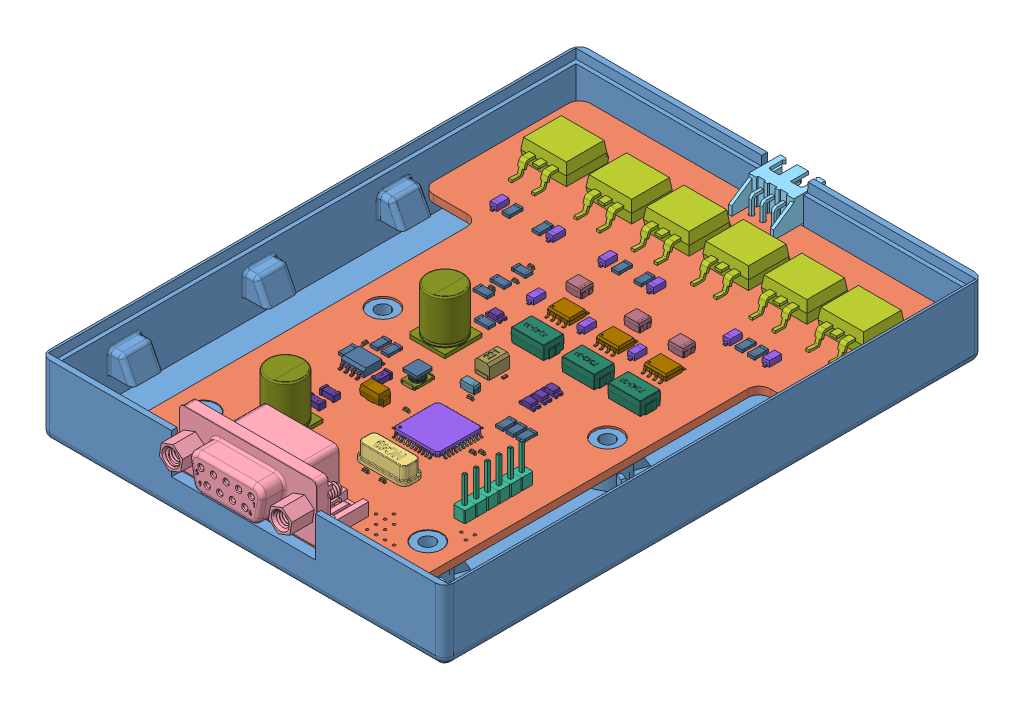
SolidWorks assembly Общая сборка, configuration По умолчанию. Lengths in mm.
Overall size (90 25.25 126.59).
248 component instances, 92 part files, 4 mates.
Components (placement in the parent):
- основание-1: основание [По умолчанию] at origin size (90 16 120)
- PCB_BLDC421232_СБ-1: PCB_BLDC421232_СБ [По умолчанию] at (1.5 8.4374 57.75) x (0 0 -1) z (0 1 0) size (126.59 85 25.25)
  - Board-1: Board [По умолчанию] at origin size (115 85 1.69)
  - ZQ1-1: ZQ1 [По умолчанию] at origin size (4.65 11.35 16.3)
    - User_Library-HC49_Crystal-1: User_Library-HC49_Crystal [По умолчанию] at (22.338 -6.587 0) x (0 1 0) z (1 0 0) size (11.35 16.3 4.65)
  - XS1-1: XS1 [По умолчанию] at origin size (16.7 30.5 16.4)
    - User_Library-DB-9F-1: User_Library-DB-9F [По умолчанию] at (-1.1101 1.395 6.3) x (0 -1 0) z (-1 0 0) size (30.5 16.4 16.7)
  - XP2-1: XP2 [По умолчанию] at origin size (11.5 10 9.25)
    - User_Library-DS1069-3_CWF-3R-1: User_Library-DS1069-3_CWF-3R [По умолчанию] at (111.5999 -2.9999 0) x (0 1 0) z (0 0 1) size (10 11.5 9.25)
  - XP1-1: XP1 [По умолчанию] at origin size (15.24 2.54 11.54)
    - User_Library-PLS-2-1: User_Library-PLS-2 [По умолчанию] at (19.9299 -25.8001 0) x (1 0 0) z (0 -1 0) size (5.08 11.54 2.54)
    - User_Library-PLS-2-2: User_Library-PLS-2 [По умолчанию] at (25.0099 -25.8001 0) x (1 0 0) z (0 -1 0) size (5.08 11.54 2.54)
    - User_Library-PLS-2-3: User_Library-PLS-2 [По умолчанию] at (30.0899 -25.8001 0) x (1 0 0) z (0 -1 0) size (5.08 11.54 2.54)
  - VT6-1: VT6 [По умолчанию] at origin size (15.26 10.16 5.02)
    - SW3dPS-DPAK-1: SW3dPS-DPAK [По умолчанию] at (100.6751 -33.2751 2.5) x (0 -1 0) z (-1 0 0) size (10.16 5.02 15.26)
  - VT5-1: VT5 [По умолчанию] at origin size (15.26 10.16 5.02)
    - SW3dPS-DPAK-1: SW3dPS-DPAK [По умолчанию] at (100.5951 -20.7351 2.5) x (0 -1 0) z (-1 0 0) size (10.16 5.02 15.26)
  - VT4-1: VT4 [По умолчанию] at origin size (15.26 10.16 5.02)
    - SW3dPS-DPAK-1: SW3dPS-DPAK [По умолчанию] at (100.5951 -7.7351 2.5) x (0 -1 0) z (-1 0 0) size (10.16 5.02 15.26)
  - VT3-1: VT3 [По умолчанию] at origin size (15.26 10.16 5.02)
    - SW3dPS-DPAK-1: SW3dPS-DPAK [По умолчанию] at (100.5951 5.5149 2.5) x (0 -1 0) z (-1 0 0) size (10.16 5.02 15.26)
  - VT2-1: VT2 [По умолчанию] at origin size (15.26 10.16 5.02)
    - SW3dPS-DPAK-1: SW3dPS-DPAK [По умолчанию] at (100.4251 18.1019 2.5) x (0 -1 0) z (-1 0 0) size (10.16 5.02 15.26)
  - VT1-1: VT1 [По умолчанию] at origin size (15.26 10.16 5.02)
    - SW3dPS-DPAK-1: SW3dPS-DPAK [По умолчанию] at (100.3451 32.5619 2.5) x (0 -1 0) z (-1 0 0) size (10.16 5.02 15.26)
  - VD10-1: VD10 [По умолчанию] at origin size (3.7 1.6 1.27)
    - SW3DPS-SOD123-DEFAULT-1: SW3DPS-SOD123-DEFAULT [По умолчанию] at (85.3569 -28.75 0) x (-1 0 0) z (0 1 0) size (3.7 1.27 1.6)
  - VD9-1: VD9 [По умолчанию] at origin size (3.7 1.6 1.27)
    - SW3DPS-SOD123-DEFAULT-1: SW3DPS-SOD123-DEFAULT [По умолчанию] at (85.1069 -20.25 0) x (-1 0 0) z (0 1 0) size (3.7 1.27 1.6)
  - VD8-1: VD8 [По умолчанию] at origin size (3.7 1.6 1.27)
    - SW3DPS-SOD123-DEFAULT-1: SW3DPS-SOD123-DEFAULT [По умолчанию] at (86.6069 -1.75 0) x (-1 0 0) z (0 1 0) size (3.7 1.27 1.6)
  - VD7-1: VD7 [По умолчанию] at origin size (3.7 1.6 1.27)
    - SW3DPS-SOD123-DEFAULT-1: SW3DPS-SOD123-DEFAULT [По умолчанию] at (86.3569 8.75 0) x (-1 0 0) z (0 1 0) size (3.7 1.27 1.6)
  - VD6-1: VD6 [По умолчанию] at origin size (3.7 1.6 1.27)
    - SW3DPS-SOD123-DEFAULT-1: SW3DPS-SOD123-DEFAULT [По умолчанию] at (85.3649 19.377 0) x (-1 0 0) z (0 1 0) size (3.7 1.27 1.6)
  - VD5-1: VD5 [По умолчанию] at origin size (3.7 1.6 1.27)
    - SW3DPS-SOD123-DEFAULT-1: SW3DPS-SOD123-DEFAULT [По умолчанию] at (85.1069 31.6269 0) x (-1 0 0) z (0 1 0) size (3.7 1.27 1.6)
  - VD4-1: VD4 [По умолчанию] at origin size (3.7 1.6 1.27)
    - SW3DPS-SOD123-DEFAULT-1: SW3DPS-SOD123-DEFAULT [По умолчанию] at (71.6431 -12.5 0) x (1 0 0) z (0 -1 0) size (3.7 1.27 1.6)
  - VD3-1: VD3 [По умолчанию] at origin size (3.7 1.6 1.27)
    - SW3DPS-SOD123-DEFAULT-1: SW3DPS-SOD123-DEFAULT [По умолчанию] at (71.1431 -1.75 0) x (1 0 0) z (0 -1 0) size (3.7 1.27 1.6)
  - VD2-1: VD2 [По умолчанию] at origin size (3.7 1.6 1.27)
    - SW3DPS-SOD123-DEFAULT-1: SW3DPS-SOD123-DEFAULT [По умолчанию] at (71.1431 9.5 0) x (1 0 0) z (0 -1 0) size (3.7 1.27 1.6)
  - VD1-1: VD1 [По умолчанию] at origin size (2.6 5.21 2.43)
    - SW3dPS-DO-214AC_SMA-1: SW3dPS-DO-214AC_SMA [По умолчанию] at (33.9999 8.2001 1.5) x (1 0 0) z (0 0 1) size (2.6 5.21 2.43)
  - R24-1: R24 [По умолчанию] at origin size (1.66 3.1 0.62)
    - ЁхчшёЄюЁ-1206-1: ЁхчшёЄюЁ-1206 [По умолчанию] at (60.7501 10.4999 0.09) x (0 -1 0) z (-1 0 0) size (3.1 0.62 1.66)
  - R23-1: R23 [По умолчанию] at origin size (3.1 1.66 0.62)
    - ЁхчшёЄюЁ-1206-1: ЁхчшёЄюЁ-1206 [По умолчанию] at (85.2501 -25.7499 0.09) x (1 0 0) z (0 -1 0) size (3.1 0.62 1.66)
  - R22-1: R22 [По умолчанию] at origin size (3.1 1.66 0.62)
    - ЁхчшёЄюЁ-1206-1: ЁхчшёЄюЁ-1206 [По умолчанию] at (85.2501 -22.9999 0.09) x (1 0 0) z (0 -1 0) size (3.1 0.62 1.66)
  - R21-1: R21 [По умолчанию] at origin size (3.1 1.66 0.62)
    - ЁхчшёЄюЁ-1206-1: ЁхчшёЄюЁ-1206 [По умолчанию] at (86.7501 1.0001 0.09) x (1 0 0) z (0 -1 0) size (3.1 0.62 1.66)
  - R20-1: R20 [По умолчанию] at origin size (3.1 1.66 0.62)
    - ЁхчшёЄюЁ-1206-1: ЁхчшёЄюЁ-1206 [По умолчанию] at (86.5001 5.7501 0.09) x (1 0 0) z (0 -1 0) size (3.1 0.62 1.66)
  - R19-1: R19 [По умолчанию] at origin size (3.1 1.66 0.62)
    - ЁхчшёЄюЁ-1206-1: ЁхчшёЄюЁ-1206 [По умолчанию] at (85.2501 22.1271 0.09) x (1 0 0) z (0 -1 0) size (3.1 0.62 1.66)
  - R18-1: R18 [По умолчанию] at origin size (3.1 1.66 0.62)
    - ЁхчшёЄюЁ-1206-1: ЁхчшёЄюЁ-1206 [По умолчанию] at (85.2501 28.8771 0.09) x (1 0 0) z (0 -1 0) size (3.1 0.62 1.66)
  - R17-1: R17 [По умолчанию] at origin size (1 0.5 0.25)
    - User_Library-d0402h025-1: User_Library-d0402h025 [По умолчанию] at (52.6499 -1.9999 0) x (-1 0 0) z (0 0 1) size (1 0.5 0.25)
  - R16-1: R16 [По умолчанию] at origin size (3.1 1.66 0.62)
    - ЁхчшёЄюЁ-1206-1: ЁхчшёЄюЁ-1206 [По умолчанию] at (73.7501 20.9999 -1.7814) x (1 0 0) z (0 1 0) size (3.1 0.62 1.66)
  - R15-1: R15 [По умолчанию] at origin size (3.1 1.66 0.62)
    - ЁхчшёЄюЁ-1206-1: ЁхчшёЄюЁ-1206 [По умолчанию] at (73.7501 23.7499 -1.7814) x (1 0 0) z (0 1 0) size (3.1 0.62 1.66)
  - R14-1: R14 [По умолчанию] at origin size (3.1 1.66 0.62)
    - ЁхчшёЄюЁ-1206-1: ЁхчшёЄюЁ-1206 [По умолчанию] at (73.7501 26.2499 -1.7814) x (1 0 0) z (0 1 0) size (3.1 0.62 1.66)
  - R13-1: R13 [По умолчанию] at origin size (1.66 3.1 0.62)
    - ЁхчшёЄюЁ-1206-1: ЁхчшёЄюЁ-1206 [По умолчанию] at (74.7499 16.2501 0.09) x (0 1 0) z (1 0 0) size (3.1 0.62 1.66)
  - R12-1: R12 [По умолчанию] at origin size (1.66 3.1 0.62)
    - ЁхчшёЄюЁ-1206-1: ЁхчшёЄюЁ-1206 [По умолчанию] at (70.2499 16.5001 0.09) x (0 1 0) z (1 0 0) size (3.1 0.62 1.66)
  - R11-1: R11 [По умолчанию] at origin size (3.1 1.66 0.62)
    - ЁхчшёЄюЁ-1206-1: ЁхчшёЄюЁ-1206 [По умолчанию] at (67.0001 20.9999 -1.7814) x (1 0 0) z (0 1 0) size (3.1 0.62 1.66)
  - R10-1: R10 [По умолчанию] at origin size (3.1 1.66 0.62)
    - ЁхчшёЄюЁ-1206-1: ЁхчшёЄюЁ-1206 [По умолчанию] at (67.0001 23.7499 -1.7814) x (1 0 0) z (0 1 0) size (3.1 0.62 1.66)
  - R9-1: R9 [По умолчанию] at origin size (3.1 1.66 0.62)
    - ЁхчшёЄюЁ-1206-1: ЁхчшёЄюЁ-1206 [По умолчанию] at (67.0001 26.2499 -1.7814) x (1 0 0) z (0 1 0) size (3.1 0.62 1.66)
  - R8-1: R8 [По умолчанию] at origin size (1.66 3.1 0.62)
    - ЁхчшёЄюЁ-1206-1: ЁхчшёЄюЁ-1206 [По умолчанию] at (66.4999 16.5001 0.09) x (0 1 0) z (1 0 0) size (3.1 0.62 1.66)
  - R7-1: R7 [По умолчанию] at origin size (1 0.5 0.25)
    - User_Library-d0402h025-1: User_Library-d0402h025 [По умолчанию] at (25.8501 -3.0001 0) x (1 0 0) z (0 0 1) size (1 0.5 0.25)
  - R6-1: R6 [По умолчанию] at origin size (3.1 1.66 0.62)
    - ЁхчшёЄюЁ-1206-1: ЁхчшёЄюЁ-1206 [По умолчанию] at (45.0001 15.5001 0.09) x (1 0 0) z (0 -1 0) size (3.1 0.62 1.66)
  - R5-1: R5 [По умолчанию] at origin size (3.1 1.66 0.62)
    - ЁхчшёЄюЁ-1206-1: ЁхчшёЄюЁ-1206 [По умолчанию] at (45.0001 18.0001 0.09) x (1 0 0) z (0 -1 0) size (3.1 0.62 1.66)
  - R4-1: R4 [По умолчанию] at origin size (3.1 1.66 0.62)
    - ЁхчшёЄюЁ-1206-1: ЁхчшёЄюЁ-1206 [По умолчанию] at (40.0001 20.0001 0.09) x (1 0 0) z (0 -1 0) size (3.1 0.62 1.66)
  - R3-1: R3 [По умолчанию] at origin size (3.1 1.66 0.62)
    - ЁхчшёЄюЁ-1206-1: ЁхчшёЄюЁ-1206 [По умолчанию] at (43.4999 -16.0001 0.09) x (-1 0 0) z (0 1 0) size (3.1 0.62 1.66)
  - R2-1: R2 [По умолчанию] at origin size (3.1 1.66 0.62)
    - ЁхчшёЄюЁ-1206-1: ЁхчшёЄюЁ-1206 [По умолчанию] at (43.4999 -11.5001 0.09) x (-1 0 0) z (0 1 0) size (3.1 0.62 1.66)
  - R1-1: R1 [По умолчанию] at origin size (3.1 1.66 0.62)
    - ЁхчшёЄюЁ-1206-1: ЁхчшёЄюЁ-1206 [По умолчанию] at (43.4999 -13.7501 0.09) x (-1 0 0) z (0 1 0) size (3.1 0.62 1.66)
  - L2-1: L2 [По умолчанию] at origin size (4.65 3.2 3.08)
    - ╚эфєъЄштэюёЄ№NLC453232-1: ╚эфєъЄштэюёЄ№NLC453232 [По умолчанию] at (52.5359 0.699 0.05) x (1 0 0) z (0 -1 0) size (4.65 3.08 3.2)
  - L1-1: L1 [По умолчанию] at origin size (4.6 3.2 2.6)
    - User_Library-lqh4c_1812-1: User_Library-lqh4c_1812 [По умолчанию] at (42.25 7 0) x (1 0 0) z (0 0 1) size (4.6 3.2 2.6)
      - User_Library-lqh4c_1812_Torus-1: User_Library-lqh4c_1812_Torus [По умолчанию] at origin size (2.9 2.9 0.1)
      - User_Library-lqh4c_1812_Torus001-1: User_Library-lqh4c_1812_Torus001 [По умолчанию] at origin size (2.9 2.9 0.1)
      - User_Library-lqh4c_1812_Torus002-1: User_Library-lqh4c_1812_Torus002 [По умолчанию] at origin size (2.9 2.9 0.1)
      - User_Library-lqh4c_1812_Torus003-1: User_Library-lqh4c_1812_Torus003 [По умолчанию] at origin size (2.9 2.9 0.1)
      - User_Library-lqh4c_1812_Torus004-1: User_Library-lqh4c_1812_Torus004 [По умолчанию] at origin size (2.9 2.9 0.1)
      - User_Library-lqh4c_1812_Torus005-1: User_Library-lqh4c_1812_Torus005 [По умолчанию] at origin size (2.9 2.9 0.1)
      - User_Library-lqh4c_1812_Torus006-1: User_Library-lqh4c_1812_Torus006 [По умолчанию] at origin size (2.9 2.9 0.1)
      - User_Library-lqh4c_1812_Torus007-1: User_Library-lqh4c_1812_Torus007 [По умолчанию] at origin size (2.9 2.9 0.1)
      - User_Library-lqh4c_1812_Torus008-1: User_Library-lqh4c_1812_Torus008 [По умолчанию] at origin size (2.9 2.9 0.1)
      - User_Library-lqh4c_1812_Torus009-1: User_Library-lqh4c_1812_Torus009 [По умолчанию] at origin size (2.9 2.9 0.1)
      - User_Library-lqh4c_1812_Torus010-1: User_Library-lqh4c_1812_Torus010 [По умолчанию] at origin size (2.9 2.9 0.1)
      - User_Library-lqh4c_1812_Torus011-1: User_Library-lqh4c_1812_Torus011 [По умолчанию] at origin size (2.9 2.9 0.1)
      - User_Library-lqh4c_1812_Torus012-1: User_Library-lqh4c_1812_Torus012 [По умолчанию] at origin size (2.9 2.9 0.1)
      - User_Library-lqh4c_1812_Torus013-1: User_Library-lqh4c_1812_Torus013 [По умолчанию] at origin size (2.9 2.9 0.1)
      - User_Library-lqh4c_1812_Torus014-1: User_Library-lqh4c_1812_Torus014 [По умолчанию] at origin size (2.9 2.9 0.1)
      - User_Library-lqh4c_1812_Fillet001-1: User_Library-lqh4c_1812_Fillet001 [По умолчанию] at origin size (3.5 3.2 0.6)
      - User_Library-lqh4c_1812_Cube002-1: User_Library-lqh4c_1812_Cube002 [По умолчанию] at origin size (0.3 2.2 0.65)
      - User_Library-lqh4c_1812_Cube003-1: User_Library-lqh4c_1812_Cube003 [По умолчанию] at origin size (0.3 2.2 0.65)
      - User_Library-lqh4c_1812_Cube004-1: User_Library-lqh4c_1812_Cube004 [По умолчанию] at origin size (1 2.2 0.3)
      - User_Library-lqh4c_1812_Cube005-1: User_Library-lqh4c_1812_Cube005 [По умолчанию] at origin size (1 2.2 0.3)
      - User_Library-lqh4c_1812_Cylinder002-1: User_Library-lqh4c_1812_Cylinder002 [По умолчанию] at origin
      - User_Library-lqh4c_1812_Cylinder003-1: User_Library-lqh4c_1812_Cylinder003 [По умолчанию] at origin
      - User_Library-lqh4c_1812_Cylinder004-1: User_Library-lqh4c_1812_Cylinder004 [По умолчанию] at origin
      - User_Library-lqh4c_1812_Fillet002-1: User_Library-lqh4c_1812_Fillet002 [По умолчанию] at origin size (0.09 0.09 0.1)
      - User_Library-lqh4c_1812_Cut002-1: User_Library-lqh4c_1812_Cut002 [По умолчанию] at origin size (4.5 3.2 0.53)
  - HL4-1: HL4 [По умолчанию] at origin size (1.6 3.2 1.1)
    - CircuitWorks-LED_1206-1: CircuitWorks-LED_1206 [По умолчанию] at (63.2501 10.4999 0) x (1 0 0) z (0 -1 0) size (1.6 1.1 3.2)
  - HL3-1: HL3 [По умолчанию] at origin size (1.6 3.2 1.1)
    - CircuitWorks-LED_1206-1: CircuitWorks-LED_1206 [По умолчанию] at (54.9999 -10.2499 0) x (-1 0 0) z (0 1 0) size (1.6 1.1 3.2)
  - HL2-1: HL2 [По умолчанию] at origin size (1.6 3.2 1.1)
    - CircuitWorks-LED_1206-1: CircuitWorks-LED_1206 [По умолчанию] at (52.4999 -10.2499 0) x (-1 0 0) z (0 1 0) size (1.6 1.1 3.2)
  - HL1-1: HL1 [По умолчанию] at origin size (1.6 3.2 1.1)
    - CircuitWorks-LED_1206-1: CircuitWorks-LED_1206 [По умолчанию] at (49.9999 -10.2499 0) x (-1 0 0) z (0 1 0) size (1.6 1.1 3.2)
  - DD2-1: DD2 [По умолчанию] at origin size (12 12 1.1)
    - User_Library-TQFP-44-1-1: User_Library-TQFP-44-1 [По умолчанию] at (28.4999 0.7811 0) x (0 -1 0) z (0 0 1) size (12 12 1.1)
      - User_Library-TQFP-44-1_pin001-1: User_Library-TQFP-44-1_pin001 [По умолчанию] at origin size (0.36 1 0.6)
      - User_Library-TQFP-44-1_pin021-1: User_Library-TQFP-44-1_pin021 [По умолчанию] at origin size (1 0.36 0.6)
      - User_Library-TQFP-44-1_pin022-1: User_Library-TQFP-44-1_pin022 [По умолчанию] at origin size (1 0.36 0.6)
      - User_Library-TQFP-44-1_pin020-1: User_Library-TQFP-44-1_pin020 [По умолчанию] at origin size (1 0.36 0.6)
      - User_Library-TQFP-44-1_pin019-1: User_Library-TQFP-44-1_pin019 [По умолчанию] at origin size (1 0.36 0.6)
      - User_Library-TQFP-44-1_pin018-1: User_Library-TQFP-44-1_pin018 [По умолчанию] at origin size (1 0.36 0.6)
      - User_Library-TQFP-44-1_pin017-1: User_Library-TQFP-44-1_pin017 [По умолчанию] at origin size (1 0.36 0.6)
      - User_Library-TQFP-44-1_pin024-1: User_Library-TQFP-44-1_pin024 [По умолчанию] at origin size (0.36 1 0.6)
      - User_Library-TQFP-44-1_pin023-1: User_Library-TQFP-44-1_pin023 [По умолчанию] at origin size (0.36 1 0.6)
      - User_Library-TQFP-44-1_pin007-1: User_Library-TQFP-44-1_pin007 [По умолчанию] at origin size (0.36 1 0.6)
      - User_Library-TQFP-44-1_pin003-1: User_Library-TQFP-44-1_pin003 [По умолчанию] at origin size (0.36 1 0.6)
      - User_Library-TQFP-44-1_pin015-1: User_Library-TQFP-44-1_pin015 [По умолчанию] at origin size (1 0.36 0.6)
      - User_Library-TQFP-44-1_pin014-1: User_Library-TQFP-44-1_pin014 [По умолчанию] at origin size (1 0.36 0.6)
      - User_Library-TQFP-44-1_pin013-1: User_Library-TQFP-44-1_pin013 [По умолчанию] at origin size (1 0.36 0.6)
      - User_Library-TQFP-44-1_pin012-1: User_Library-TQFP-44-1_pin012 [По умолчанию] at origin size (1 0.36 0.6)
      - User_Library-TQFP-44-1_pin011-1: User_Library-TQFP-44-1_pin011 [По умолчанию] at origin size (0.36 1 0.6)
      - User_Library-TQFP-44-1_pin010-1: User_Library-TQFP-44-1_pin010 [По умолчанию] at origin size (0.36 1 0.6)
      - User_Library-TQFP-44-1_pin009-1: User_Library-TQFP-44-1_pin009 [По умолчанию] at origin size (0.36 1 0.6)
      - User_Library-TQFP-44-1_pin008-1: User_Library-TQFP-44-1_pin008 [По умолчанию] at origin size (0.36 1 0.6)
      - User_Library-TQFP-44-1_pin006-1: User_Library-TQFP-44-1_pin006 [По умолчанию] at origin size (0.36 1 0.6)
      - User_Library-TQFP-44-1_pin005-1: User_Library-TQFP-44-1_pin005 [По умолчанию] at origin size (0.36 1 0.6)
      - User_Library-TQFP-44-1_pin004-1: User_Library-TQFP-44-1_pin004 [По умолчанию] at origin size (0.36 1 0.6)
      - User_Library-TQFP-44-1_pin002-1: User_Library-TQFP-44-1_pin002 [По умолчанию] at origin size (0.36 1 0.6)
      - User_Library-TQFP-44-1_pin016-1: User_Library-TQFP-44-1_pin016 [По умолчанию] at origin size (1 0.36 0.6)
      - User_Library-TQFP-44-1_pin027-1: User_Library-TQFP-44-1_pin027 [По умолчанию] at origin size (0.36 1 0.6)
      - User_Library-TQFP-44-1_pin037-1: User_Library-TQFP-44-1_pin037 [По умолчанию] at origin size (1 0.36 0.6)
      - User_Library-TQFP-44-1_pin025-1: User_Library-TQFP-44-1_pin025 [По умолчанию] at origin size (0.36 1 0.6)
      - User_Library-TQFP-44-1_pin026-1: User_Library-TQFP-44-1_pin026 [По умолчанию] at origin size (0.36 1 0.6)
      - User_Library-TQFP-44-1_pin036-1: User_Library-TQFP-44-1_pin036 [По умолчанию] at origin size (1 0.36 0.6)
      - User_Library-TQFP-44-1_pin035-1: User_Library-TQFP-44-1_pin035 [По умолчанию] at origin size (1 0.36 0.6)
      - User_Library-TQFP-44-1_pin034-1: User_Library-TQFP-44-1_pin034 [По умолчанию] at origin size (1 0.36 0.6)
      - User_Library-TQFP-44-1_pin033-1: User_Library-TQFP-44-1_pin033 [По умолчанию] at origin size (0.36 1 0.6)
      - User_Library-TQFP-44-1_pin032-1: User_Library-TQFP-44-1_pin032 [По умолчанию] at origin size (0.36 1 0.6)
      - User_Library-TQFP-44-1_pin031-1: User_Library-TQFP-44-1_pin031 [По умолчанию] at origin size (0.36 1 0.6)
      - User_Library-TQFP-44-1_pin030-1: User_Library-TQFP-44-1_pin030 [По умолчанию] at origin size (0.36 1 0.6)
      - User_Library-TQFP-44-1_pin029-1: User_Library-TQFP-44-1_pin029 [По умолчанию] at origin size (0.36 1 0.6)
      - User_Library-TQFP-44-1_pin028-1: User_Library-TQFP-44-1_pin028 [По умолчанию] at origin size (0.36 1 0.6)
      - User_Library-TQFP-44-1_pin038-1: User_Library-TQFP-44-1_pin038 [По умолчанию] at origin size (1 0.36 0.6)
      - User_Library-TQFP-44-1_pin044-1: User_Library-TQFP-44-1_pin044 [По умолчанию] at origin size (1 0.36 0.6)
      - User_Library-TQFP-44-1_pin043-1: User_Library-TQFP-44-1_pin043 [По умолчанию] at origin size (1 0.36 0.6)
      - User_Library-TQFP-44-1_pin042-1: User_Library-TQFP-44-1_pin042 [По умолчанию] at origin size (1 0.36 0.6)
      - User_Library-TQFP-44-1_pin041-1: User_Library-TQFP-44-1_pin041 [По умолчанию] at origin size (1 0.36 0.6)
      - User_Library-TQFP-44-1_pin040-1: User_Library-TQFP-44-1_pin040 [По умолчанию] at origin size (1 0.36 0.6)
      - User_Library-TQFP-44-1_pin039-1: User_Library-TQFP-44-1_pin039 [По умолчанию] at origin size (1 0.36 0.6)
      - User_Library-TQFP-44-1_Body-1: User_Library-TQFP-44-1_Body [По умолчанию] at origin size (10 10 1)
  - DD1-1: DD1 [По умолчанию] at origin size (4.9 5.78 1.45)
    - SW3DPS-SO-8-DEFAULT-1: SW3DPS-SO-8-DEFAULT [По умолчанию] at (16.2391 5.397 0) x (0 -1 0) z (-1 0 0) size (5.78 1.45 4.9)
  - DA4-1: DA4 [По умолчанию] at origin size (5.78 4.9 1.45)
    - SW3DPS-SO-8-DEFAULT-1: SW3DPS-SO-8-DEFAULT [По умолчанию] at (68.8529 -16.5509 0) x (1 0 0) z (0 -1 0) size (5.78 1.45 4.9)
  - DA3-1: DA3 [По умолчанию] at origin size (5.78 4.9 1.45)
    - SW3DPS-SO-8-DEFAULT-1: SW3DPS-SO-8-DEFAULT [По умолчанию] at (68.853 -5.9909 0) x (1 0 0) z (0 -1 0) size (5.78 1.45 4.9)
  - DA2-1: DA2 [По умолчанию] at origin size (5.78 4.9 1.45)
    - SW3DPS-SO-8-DEFAULT-1: SW3DPS-SO-8-DEFAULT [По умолчанию] at (68.903 4.9491 0) x (1 0 0) z (0 -1 0) size (5.78 1.45 4.9)
  - DA1-1: DA1 [По умолчанию] at origin size (6.2 5 1.75)
    - User_Library-HSOP8-1: User_Library-HSOP8 [По умолчанию] at (38.75 16 0) x (-1 0 0) z (0 1 0) size (6.2 1.75 5)
      - User_Library-HSOP8_part_hsop8_____________-1: User_Library-HSOP8_part_hsop8_____________ [По умолчанию] at origin size (4 1.75 5)
      - User_Library-HSOP8_Assy_fuss_hsop8_____________-1: User_Library-HSOP8_Assy_fuss_hsop8_____________ [По умолчанию] at (2 0 0) size (1.1 0.95 4.25)
        - User_Library-HSOP8_Fuss_hsop8_____________-1: User_Library-HSOP8_Fuss_hsop8_____________ [По умолчанию] at (0 0 -0.635) size (1.1 0.95 0.44)
        - User_Library-HSOP8_Fuss_hsop8_____________-2: User_Library-HSOP8_Fuss_hsop8_____________ [По умолчанию] at (0 0 0.635) size (1.1 0.95 0.44)
        - User_Library-HSOP8_Fuss_hsop8_____________-3: User_Library-HSOP8_Fuss_hsop8_____________ [По умолчанию] at (0 0 1.905) size (1.1 0.95 0.44)
        - User_Library-HSOP8_Fuss_hsop8_____________-4: User_Library-HSOP8_Fuss_hsop8_____________ [По умолчанию] at (0 0 -1.905) size (1.1 0.95 0.44)
        - User_Library-HSOP8_Fuss_hsop8_____________-5: User_Library-HSOP8_Fuss_hsop8_____________ [По умолчанию] at (0 0 -0.635) size (1.1 0.95 0.44)
        - User_Library-HSOP8_Fuss_hsop8_____________-6: User_Library-HSOP8_Fuss_hsop8_____________ [По умолчанию] at (0 0 0.635) size (1.1 0.95 0.44)
      - User_Library-HSOP8_Assy_fuss_hsop8_____________-2: User_Library-HSOP8_Assy_fuss_hsop8_____________ [По умолчанию] at (-2 0 0) x (-1 0 0) z (0 0 -1) size (1.1 0.95 4.25)
        - User_Library-HSOP8_Fuss_hsop8_____________-1: User_Library-HSOP8_Fuss_hsop8_____________ [По умолчанию] at (0 0 -0.635) size (1.1 0.95 0.44)
        - User_Library-HSOP8_Fuss_hsop8_____________-2: User_Library-HSOP8_Fuss_hsop8_____________ [По умолчанию] at (0 0 0.635) size (1.1 0.95 0.44)
        - User_Library-HSOP8_Fuss_hsop8_____________-3: User_Library-HSOP8_Fuss_hsop8_____________ [По умолчанию] at (0 0 1.905) size (1.1 0.95 0.44)
        - User_Library-HSOP8_Fuss_hsop8_____________-4: User_Library-HSOP8_Fuss_hsop8_____________ [По умолчанию] at (0 0 -1.905) size (1.1 0.95 0.44)
        - User_Library-HSOP8_Fuss_hsop8_____________-5: User_Library-HSOP8_Fuss_hsop8_____________ [По умолчанию] at (0 0 -0.635) size (1.1 0.95 0.44)
        - User_Library-HSOP8_Fuss_hsop8_____________-6: User_Library-HSOP8_Fuss_hsop8_____________ [По умолчанию] at (0 0 0.635) size (1.1 0.95 0.44)
  - C23-1: C23 [По умолчанию] at origin size (0.56 1.48 0.53)
    - User_Library-User_Library-0402_Cap-1: User_Library-User_Library-0402_Cap [По умолчанию] at (35.4789 -14.0749 0) x (0 -1 0) z (0 0 1) size (1.48 0.56 0.53)
  - C22-1: C22 [По умолчанию] at origin size (0.56 1.48 0.53)
    - User_Library-User_Library-0402_Cap-1: User_Library-User_Library-0402_Cap [По умолчанию] at (35.2539 2.5001 0) x (0 -1 0) z (0 0 1) size (1.48 0.56 0.53)
  - C21-1: C21 [По умолчанию] at origin size (0.56 1.48 0.53)
    - User_Library-User_Library-0402_Cap-1: User_Library-User_Library-0402_Cap [По умолчанию] at (34.4961 -13.0001 0) x (0 1 0) z (0 0 1) size (1.48 0.56 0.53)
  - C20-1: C20 [По умолчанию] at origin size (1.48 0.56 0.53)
    - User_Library-User_Library-0402_Cap-1: User_Library-User_Library-0402_Cap [По умолчанию] at (26.7499 -4.4961 0) x (1 0 0) z (0 0 1) size (1.48 0.56 0.53)
  - C19-1: C19 [По умолчанию] at origin size (2.8 3.49 1.91)
    - User_Library-cap_b-1: User_Library-cap_b [По умолчанию] at (77.4751 -16.5751 0) x (0 1 0) z (1 0 0) size (3.49 1.91 2.8)
  - C18-1: C18 [По умолчанию] at origin size (2.8 3.49 1.91)
    - User_Library-cap_b-1: User_Library-cap_b [По умолчанию] at (77.3751 -6.8751 0) x (0 1 0) z (1 0 0) size (3.49 1.91 2.8)
  - C17-1: C17 [По умолчанию] at origin size (2.8 3.49 1.91)
    - User_Library-cap_b-1: User_Library-cap_b [По умолчанию] at (77.4751 6.1749 0) x (0 1 0) z (1 0 0) size (3.49 1.91 2.8)
  - C16-1: C16 [По умолчанию] at origin size (0.56 1.48 0.53)
    - User_Library-User_Library-0402_Cap-1: User_Library-User_Library-0402_Cap [По умолчанию] at (44.7461 -2.2501 0) x (0 1 0) z (0 0 1) size (1.48 0.56 0.53)
  - C15-1: C15 [По умолчанию] at origin size (1.6 3.19 1.61)
    - SW3dPS-cap_a-1: SW3dPS-cap_a [По умолчанию] at (46.4999 -0.4999 0) x (0 1 0) z (1 0 0) size (3.19 1.61 1.6)
  - C14-1: C14 [По умолчанию] at origin size (4.6 7.6 3.1)
    - User_Library-CAP_TANT_7343-31-1: User_Library-CAP_TANT_7343-31 [По умолчанию] at (62.2641 -21.1981 0) x (0 1 0) z (1 0 0) size (7.6 3.1 4.6)
  - C13-1: C13 [По умолчанию] at origin size (4.6 7.6 3.1)
    - User_Library-CAP_TANT_7343-31-1: User_Library-CAP_TANT_7343-31 [По умолчанию] at (62.2641 -10.9481 0) x (0 1 0) z (1 0 0) size (7.6 3.1 4.6)
  - C12-1: C12 [По умолчанию] at origin size (4.6 7.6 3.1)
    - User_Library-CAP_TANT_7343-31-1: User_Library-CAP_TANT_7343-31 [По умолчанию] at (62.2641 0.3209 0) x (0 1 0) z (1 0 0) size (7.6 3.1 4.6)
  - C11-1: C11 [По умолчанию] at origin size (0.56 1.48 0.53)
    - User_Library-User_Library-0402_Cap-1: User_Library-User_Library-0402_Cap [По умолчанию] at (76.7461 16.2499 0) x (0 1 0) z (0 0 1) size (1.48 0.56 0.53)
  - C10-1: C10 [По умолчанию] at origin size (0.56 1.48 0.53)
    - User_Library-User_Library-0402_Cap-1: User_Library-User_Library-0402_Cap [По умолчанию] at (18.9961 -4.6751 0) x (0 1 0) z (0 0 1) size (1.48 0.56 0.53)
  - C9-1: C9 [По умолчанию] at origin size (0.56 1.48 0.53)
    - User_Library-User_Library-0402_Cap-1: User_Library-User_Library-0402_Cap [По умолчанию] at (72.2461 15.2499 0) x (0 1 0) z (0 0 1) size (1.48 0.56 0.53)
  - C8-1: C8 [По умолчанию] at origin size (0.56 1.48 0.53)
    - User_Library-User_Library-0402_Cap-1: User_Library-User_Library-0402_Cap [По умолчанию] at (19.0039 -8.4499 0) x (0 -1 0) z (0 0 1) size (1.48 0.56 0.53)
  - C7-1: C7 [По умолчанию] at origin size (0.56 1.48 0.53)
    - User_Library-User_Library-0402_Cap-1: User_Library-User_Library-0402_Cap [По умолчанию] at (68.2461 16.4999 0) x (0 1 0) z (0 0 1) size (1.48 0.56 0.53)
  - C6-1: C6 [По умолчанию] at origin size (8.3 8.3 10.55)
    - User_Library-capasitores_electroliticos-1: User_Library-capasitores_electroliticos [По умолчанию] at (53.7251 12.3999 0) x (0 -1 0) z (0 0 -1) size (8.3 8.3 10.55)
  - C5-1: C5 [По умолчанию] at origin size (1.48 0.56 0.53)
    - User_Library-User_Library-0402_Cap-1: User_Library-User_Library-0402_Cap [По умолчанию] at (43.4999 20.0039 0) x (1 0 0) z (0 0 1) size (1.48 0.56 0.53)
  - C4-1: C4 [По умолчанию] at origin size (3.2 1.6 1.35)
    - User_Library-capc3216L-1: User_Library-capc3216L [По умолчанию] at (38.3501 11.0251 0) x (1 0 0) z (0 -1 0) size (3.2 1.35 1.6)
  - C3-1: C3 [По умолчанию] at origin size (1.6 3.2 1.35)
    - User_Library-capc3216L-1: User_Library-capc3216L [По умолчанию] at (26.2499 13.7501 0) x (0 1 0) z (1 0 0) size (3.2 1.35 1.6)
  - C2-1: C2 [По умолчанию] at origin size (1.6 3.2 1.35)
    - User_Library-capc3216L-1: User_Library-capc3216L [По умолчанию] at (29.4999 13.7501 0) x (0 1 0) z (1 0 0) size (3.2 1.35 1.6)
  - C1-1: C1 [По умолчанию] at origin size (8.3 8.3 10.55)
    - User_Library-capasitores_electroliticos-1: User_Library-capasitores_electroliticos [По умолчанию] at (19.4751 13.6499 0) x (0 -1 0) z (0 0 -1) size (8.3 8.3 10.55)
Mates (geometry in assembly coordinates):
- Параллельность1: parallel anti-aligned: plane of основание-1 through (0 1 0) normal (0 1 0); plane of PCB_BLDC421232_СБ-1/Board-1 through (32.75 6.746 55.25) normal (0 -1 0)
- Концентричный1: concentric anti-aligned: cone of основание-1 through (-23.5 8.1 5.25) axis (0 1 0); cylinder of PCB_BLDC421232_СБ-1/Board-1 through (-23.5 6.746 5.25) axis (0 -1 0) radius 3.15
- Совпадение1: coincident anti-aligned: plane of основание-1 through (-23.5 6.746 45.25) normal (0 1 0); plane of PCB_BLDC421232_СБ-1/Board-1 through (32.75 6.746 55.25) normal (0 -1 0)
- Концентричный4: concentric aligned: cylinder of основание-1 through (26.5 8.346 45.25) axis (0 -1 0) radius 1.6; cylinder of PCB_BLDC421232_СБ-1/Board-1 through (26.5 6.746 45.25) axis (0 -1 0) radius 3.15
